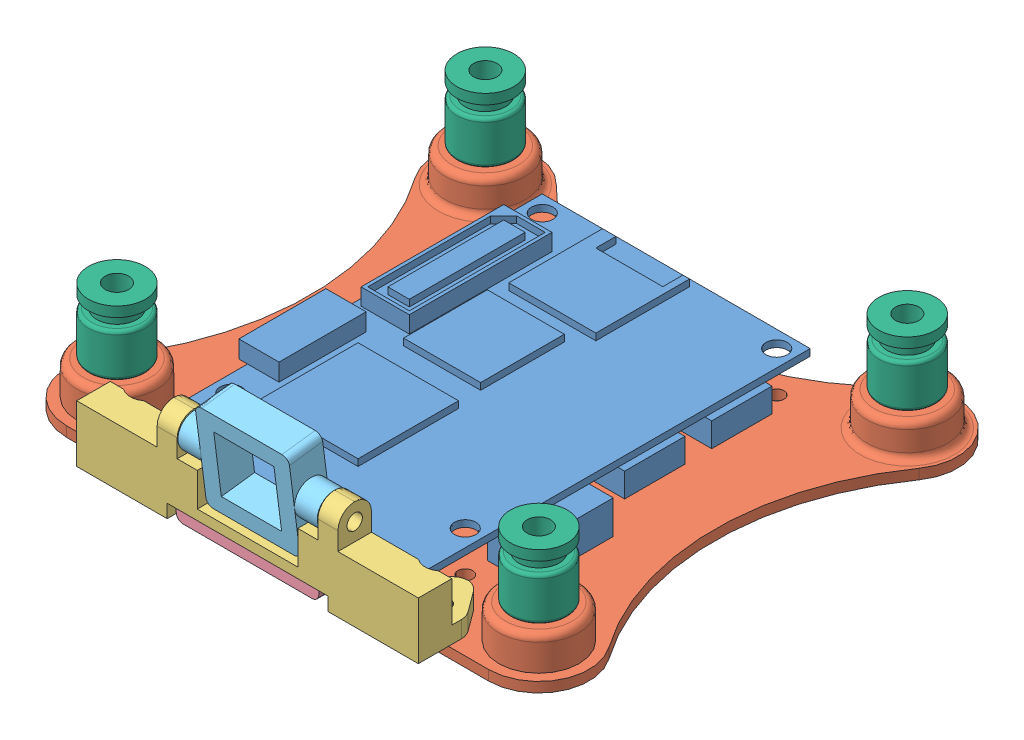
SolidWorks assembly subassem_snapdragon_flight, configuration Default. Lengths in mm.
Overall size (78 19.86 75.36).
10 component instances, 7 part files, 27 mates.
Components (placement in the parent):
- Snapdragon_Flight-1: Snapdragon_Flight [Default] at (0 6.5 7) x (0 0 1) z (-1 0 0) size (58 8.6 44.9)
- mounting_plate-1: mounting_plate [Default] x (-1 0 0) z (0 0 -1) size (78 6.5 70)
- camera_mount-1: camera_mount [Default] at (-1.502 6.35 37.6824) x (1 0 0.000747) z (-0.000747 0 1) size (52 19.7 28) (hidden)
- front_camera_mount-1: front_camera_mount [Default] at (0 1.5 39.5) x (-1 0 0) z (0 0 -1) size (51 13.7 12)
- bottom_camera_mount-1: bottom_camera_mount [Default] at (0 2 17.5) x (-1 0 0) z (0 0 -1) size (21.3 3.5 24.5)
- front_camera_mount2-1: front_camera_mount2 [Default] at (0 12.6 39.5) x (1 0 0) z (0 -0.126408 0.991978) size (20.8 14 5)
- dampener-1: dampener [Default] at (-31.5 9.75 30) x (0 -1 0) z (0 0 1) size (13 8.5 8.5)
- dampener-2: dampener [Default] at (31.5 9.75 30) x (0 -1 0) z (0.505421 0 0.862873) size (13 8.5 8.5)
- dampener-3: dampener [Default] at (-31.5 9.75 -25) x (0 -1 0) z (0 0 1) size (13 8.5 8.5)
- dampener-4: dampener [Default] at (31.5 9.75 -25) x (0 -1 0) z (0 0 1) size (13 8.5 8.5)
Mates (geometry in assembly coordinates):
- Concentric26: concentric aligned: cylinder of Snapdragon_Flight-1 through (-17.5 6.5 -19.5) axis (0 1 0) radius 1.6; cylinder of mounting_plate-1 through (-17.5 0 -19.5) axis (0 1 0) radius 1.1
- Concentric27: concentric aligned: cylinder of Snapdragon_Flight-1 through (-17.5 6.5 27) axis (0 1 0) radius 1.6; cylinder of mounting_plate-1 through (-17.5 0 27) axis (0 1 0) radius 1.1
- Distance1: distance = 5 mm anti-aligned: plane of Snapdragon_Flight-1 through (0 6.5 7) normal (0 -1 0); plane of mounting_plate-1 through (31.5 1.5 30) normal (0 1 0)
- Coincident1: coincident: plane of Snapdragon_Flight-1 through (0 7.5 7) normal (0 -1 0); plane of ? through (-0.0033 7.5 18) normal (0 1 0)
- Distance2: distance = 6.5 mm: plane of Snapdragon_Flight-1 through (-20 8.5 36) normal (0 0 1); plane of ? through (0 3.5 42.5) normal (0 0 1)
- Coincident5: coincident aligned: plane of mounting_plate-1 through (0 0 0) normal (0 1 0); plane of assembly through (0 0 0) normal (0 1 0)
- Coincident6: coincident anti-aligned: plane of mounting_plate-1 through (0 0 0) normal (0 0 -1); plane of assembly through (0 0 0) normal (0 0 1)
- Coincident7: coincident anti-aligned: plane of mounting_plate-1 through (0 0 0) normal (-1 0 0); plane of assembly through (0 0 0) normal (1 0 0)
- Concentric28: concentric aligned: cylinder of mounting_plate-1 through (22 0 35) axis (0 1 0) radius 1.1; cylinder of camera_mount-1 through (22 -0.5 35) axis (0 1 0) radius 1
- Coincident8: coincident anti-aligned: plane of mounting_plate-1 through (31.5 1.5 30) normal (0 1 0); plane of camera_mount-1 through (-27.5056 1.5 42.463) normal (0 -1 0)
- Coincident9: coincident: plane of Snapdragon_Flight-1 through (0 7.5 7) normal (-1 0 0); moEndPointRef_w of ?
- Coincident10: coincident anti-aligned: plane of mounting_plate-1 through (31.5 1.5 30) normal (0 1 0); plane of ? through (1.6695 1.5 37.9326) normal (0 -1 0)
- Concentric29: concentric aligned: cylinder of mounting_plate-1 through (22 0 35) axis (0 1 0) radius 1.1; cylinder of front_camera_mount-1 through (22 1.5 35) axis (0 1 0) radius 1.25
- Concentric30: concentric aligned: cylinder of mounting_plate-1 through (-22 0 35) axis (0 1 0) radius 1.1; cylinder of front_camera_mount-1 through (-22 1.5 35) axis (0 1 0) radius 1.25
- Coincident11: coincident anti-aligned: plane of mounting_plate-1 through (31.5 1.5 30) normal (0 1 0); plane of front_camera_mount-1 through (0 1.5 39.5) normal (0 -1 0)
- Coincident12: coincident anti-aligned: plane of front_camera_mount-1 through (0 3.5 39.5) normal (0 -1 0); plane of bottom_camera_mount-1 through (0 3.5 17.5) normal (0 1 0)
- Concentric33: concentric aligned: cylinder of front_camera_mount-1 through (8.5 8.5 39) axis (0 -1 0) radius 0.75; cylinder of bottom_camera_mount-1 through (8.5 3.5 39) axis (0 -1 0) radius 0.75
- Concentric34: concentric aligned: cylinder of front_camera_mount-1 through (-25.5 12.6 39.5) axis (1 0 0) radius 1.15; cylinder of front_camera_mount2-1 through (5.4 12.6 39.5) axis (1 0 0) radius 0.7
- Coincident13: coincident anti-aligned: plane of bottom_camera_mount-1 through (0 2 17.5) normal (-1 0 0); plane of front_camera_mount2-1 through (0 12.6 39.5) normal (1 0 0)
- Concentric35: concentric anti-aligned: cylinder of mounting_plate-1 through (31.5 0 30) axis (0 1 0) radius 3.1; cylinder of dampener-2 through (31.5 3.25 30) axis (0 -1 0) radius 3
- Coincident14: coincident anti-aligned: plane of mounting_plate-1 through (31.5 6.5 30) normal (0 1 0); plane of dampener-2 through (35.1672 6.5 27.852) normal (0 -1 0)
- Concentric36: concentric anti-aligned: cylinder of mounting_plate-1 through (-31.5 0 30) axis (0 1 0) radius 3.1; cylinder of dampener-1 through (-31.5 3.25 30) axis (0 -1 0) radius 3
- Coincident15: coincident anti-aligned: plane of mounting_plate-1 through (-31.5 6.5 30) normal (0 1 0); plane of dampener-1 through (-27.25 6.5 30) normal (0 -1 0)
- Concentric37: concentric anti-aligned: cylinder of mounting_plate-1 through (-31.5 0 -25) axis (0 1 0) radius 3.1; cylinder of dampener-3 through (-31.5 3.25 -25) axis (0 -1 0) radius 3
- Coincident16: coincident anti-aligned: plane of mounting_plate-1 through (-31.5 6.5 -25) normal (0 1 0); plane of dampener-3 through (-27.25 6.5 -25) normal (0 -1 0)
- Concentric38: concentric anti-aligned: cylinder of mounting_plate-1 through (31.5 0 -25) axis (0 1 0) radius 3.1; cylinder of dampener-4 through (31.5 3.25 -25) axis (0 -1 0) radius 3
- Coincident17: coincident anti-aligned: plane of mounting_plate-1 through (31.5 6.5 -25) normal (0 1 0); plane of dampener-4 through (35.75 6.5 -25) normal (0 -1 0)
